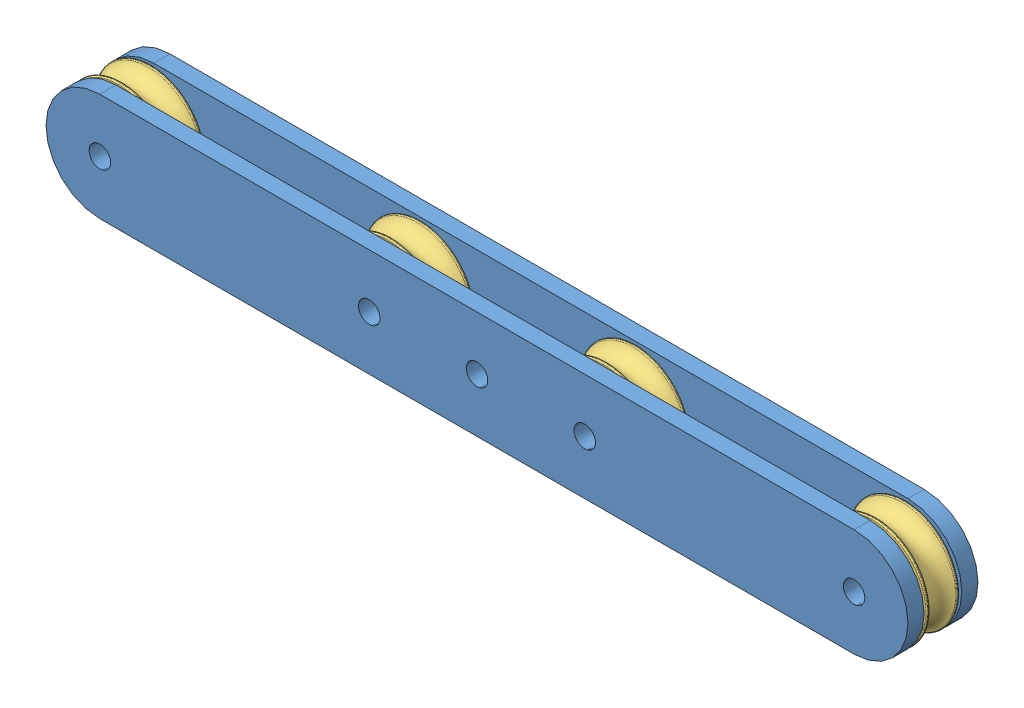
SolidWorks assembly Chariot, configuration Défaut. Lengths in mm.
Overall size (80 19.07 6.5).
22 component instances, 4 part files, 14 mates.
Components (placement in the parent):
- Rail-1: Rail [Défaut] at origin size (80 19.07 1.5)
- Rail-2: Rail [Défaut] at (0 0 5) size (80 19.07 1.5)
- Poulie-1: Poulie [Défaut] at (-35 0 3.25) size (10 10 3.5)
  - Roulement - 612-5723-1: Roulement - 612-5723 [Défaut] at origin size (6 6 3)
  - Roue-2: Roue [Défaut] at origin size (10 10 3)
  - Rondelle 4x2-1: Rondelle 4x2 [Défaut] at (0 0 1.5) size (4 4 0.25)
  - Rondelle 4x2-2: Rondelle 4x2 [Défaut] at (0 0 -1.5) x (-0.923728 -0.383049 0) z (0 0 -1) size (4 4 0.25)
- Poulie-2: Poulie [Défaut] at (-10 0 3.25) size (10 10 3.5)
  - Roulement - 612-5723-1: Roulement - 612-5723 [Défaut] at origin size (6 6 3)
  - Roue-2: Roue [Défaut] at origin size (10 10 3)
  - Rondelle 4x2-1: Rondelle 4x2 [Défaut] at (0 0 1.5) size (4 4 0.25)
  - Rondelle 4x2-2: Rondelle 4x2 [Défaut] at (0 0 -1.5) x (-0.923728 -0.383049 0) z (0 0 -1) size (4 4 0.25)
- Poulie-3: Poulie [Défaut] at (10 0 3.25) size (10 10 3.5)
  - Roulement - 612-5723-1: Roulement - 612-5723 [Défaut] at origin size (6 6 3)
  - Roue-2: Roue [Défaut] at origin size (10 10 3)
  - Rondelle 4x2-1: Rondelle 4x2 [Défaut] at (0 0 1.5) size (4 4 0.25)
  - Rondelle 4x2-2: Rondelle 4x2 [Défaut] at (0 0 -1.5) x (-0.923728 -0.383049 0) z (0 0 -1) size (4 4 0.25)
- Poulie-4: Poulie [Défaut] at (35 0 3.25) size (10 10 3.5)
  - Roulement - 612-5723-1: Roulement - 612-5723 [Défaut] at origin size (6 6 3)
  - Roue-2: Roue [Défaut] at origin size (10 10 3)
  - Rondelle 4x2-1: Rondelle 4x2 [Défaut] at (0 0 1.5) size (4 4 0.25)
  - Rondelle 4x2-2: Rondelle 4x2 [Défaut] at (0 0 -1.5) x (-0.923728 -0.383049 0) z (0 0 -1) size (4 4 0.25)
Mates (geometry in assembly coordinates):
- Coaxiale1: concentric aligned: circle of Rail-1; circle of Rail-2
- Coïncidente2: coincident aligned: plane of Rail-1 through (0 0 0) normal (0 0 1); plane of assembly through (0 0 0) normal (0 0 1)
- Coïncidente3: coincident aligned: plane of Rail-1 through (0 0 0) normal (0 1 0); plane of assembly through (0 0 0) normal (0 1 0)
- Coïncidente4: coincident aligned: plane of Rail-1 through (0 0 0) normal (1 0 0); plane of assembly through (0 0 0) normal (1 0 0)
- Coaxiale2: concentric anti-aligned: cylinder of Rail-1 through (35 0 1.5) axis (0 0 -1) radius 1; cylinder of Poulie-4/Roulement - 612-5723-1 through (35 0 3.25) axis (0 0 1) radius 1
- Coïncidente5: coincident anti-aligned: plane of Rail-1 through (-35 0 1.5) normal (0 0 1); plane of Poulie-4/Rondelle 4x2-2 through (35 0 1.5) normal (0 0 -1)
- Coaxiale3: concentric anti-aligned: cylinder of Rail-1 through (10 0 1.5) axis (0 0 -1) radius 1; cylinder of Poulie-3/Roulement - 612-5723-1 through (10 0 3.25) axis (0 0 1) radius 1
- Coaxiale4: concentric anti-aligned: cylinder of Rail-1 through (-10 0 1.5) axis (0 0 -1) radius 1; cylinder of Poulie-2/Roulement - 612-5723-1 through (-10 0 3.25) axis (0 0 1) radius 1
- Coaxiale5: concentric anti-aligned: cylinder of Rail-1 through (-35 0 1.5) axis (0 0 -1) radius 1; cylinder of Poulie-1/Roulement - 612-5723-1 through (-35 0 3.25) axis (0 0 1) radius 1
- Coïncidente6: coincident anti-aligned: plane of Rail-1 through (-35 0 1.5) normal (0 0 1); plane of Poulie-1/Rondelle 4x2-2 through (-35 0 1.5) normal (0 0 -1)
- Coïncidente7: coincident anti-aligned: plane of Rail-1 through (-35 0 1.5) normal (0 0 1); plane of Poulie-2/Rondelle 4x2-2 through (-10 0 1.5) normal (0 0 -1)
- Coïncidente8: coincident anti-aligned: plane of Rail-1 through (-35 0 1.5) normal (0 0 1); plane of Poulie-3/Rondelle 4x2-2 through (10 0 1.5) normal (0 0 -1)
- Coaxiale6: concentric aligned: cylinder of Rail-1 through (-35 0 1.5) axis (0 0 -1) radius 1; cylinder of Rail-2 through (-35 0 6.5) axis (0 0 -1) radius 1
- Coïncidente9: coincident anti-aligned: plane of Rail-2 through (-35 0 5) normal (0 0 -1); plane of Poulie-1/Rondelle 4x2-1 through (-35 0 5) normal (0 0 1)
